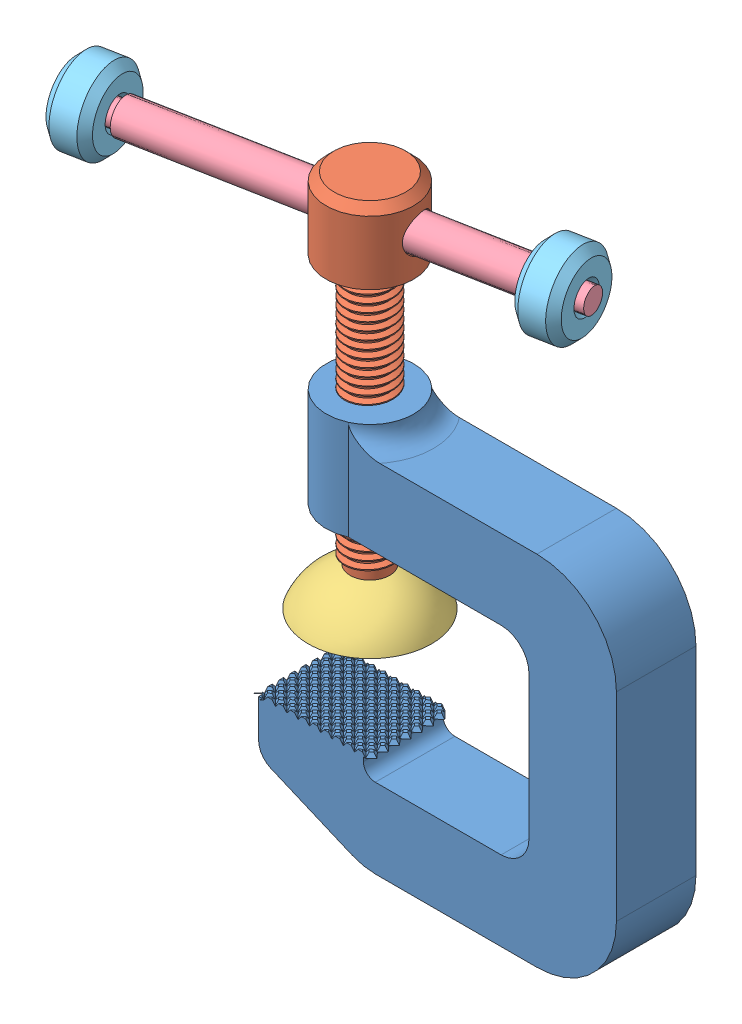
SolidWorks assembly Assem1, configuration Default. Lengths in mm.
Overall size (136.97 144.02 43.23).
6 component instances, 5 part files, 12 mates.
Components (placement in the parent):
- Part5-1: Part5 [Default] at (-108.175 29.7032 123.26) size (91.42 95.6 22.42)
- Part4-1: Part4 [Default] at (-90.175 55.0407 123.26) x (-0.186606 0 -0.982435) z (0.982435 0 -0.186606) size (22 93 22)
- Part3-1: Part3 [Default] at (-90.175 46.5848 123.26) x (0.840869 0 -0.541239) z (0.541239 0 0.840869) size (31 10.16 31)
- Part2-1: Part2 [Default] at (-43.0031 139.0407 114.3) x (-0.186606 0 -0.982435) z (0.982435 0 -0.186606) size (8.5 8.5 113)
- Part1-1: Part1 [Default] at (-153.275 139.0407 135.2454) x (0.982435 0 -0.186606) z (0.186606 0 0.982435) size (10 20 20)
- Part1-2: Part1 [Default] at (-54.1993 139.0407 116.4266) x (0.982435 0 -0.186606) z (0.186136 0.070968 0.979958) size (10 20 20)
Mates (geometry in assembly coordinates):
- Concentric1: concentric: cylinder of Part5-1 through (-90.175 100.7032 123.26) axis (0 -1 0) radius 11; cylinder of Part4-1 through (-90.175 55.0407 123.26) axis (0 -1 0) radius 11
- Coincident1: coincident: circle of Part5-1; cylinder of Part5-1 through (-90.175 100.7032 123.26) axis (0 -1 0) radius 11
- Coincident2: coincident: cylinder of Part4-1 through (-90.175 55.0407 123.26) axis (0 -1 0) radius 3; circle of Part3-1
- Concentric3: concentric: cylinder of Part4-1 through (-90.175 55.0407 123.26) axis (0 -1 0) radius 11; sphere of Part3-1
- Tangent5: tangent: circle of Part4-1; sphere of Part3-1
- Concentric4: concentric: cylinder of Part4-1 through (-100.9818 139.0407 125.3126) axis (0.982435 0 -0.186606) radius 4.5; cylinder of Part2-1 through (-43.0031 139.0407 114.3) axis (0.982435 0 -0.186606) radius 4.25
- Concentric5: concentric: cylinder of Part1-1 through (-153.275 139.0407 135.2454) axis (-0.982435 0 0.186606) radius 10; cylinder of Part1-2 through (-54.1993 139.0407 116.4266) axis (-0.982435 0 0.186606) radius 3
- Concentric6: concentric: cylinder of Part2-1 through (-43.0031 139.0407 114.3) axis (0.982435 0 -0.186606) radius 3; circle of Part1-2
- Concentric7: concentric: cylinder of Part2-1 through (-43.0031 139.0407 114.3) axis (0.982435 0 -0.186606) radius 3; cone of Part1-1 through (-143.4507 139.0407 133.3793) axis (-0.982435 0 0.186606)
- Concentric8: concentric: cylinder of Part2-1 through (-43.0031 139.0407 114.3) axis (0.982435 0 -0.186606) radius 3; cone of Part1-2 through (-44.3749 139.0407 114.5606) axis (-0.982435 0 0.186606)
- Concentric9: concentric: cylinder of Part2-1 through (-43.0031 139.0407 114.3) axis (0.982435 0 -0.186606) radius 3; cone of Part1-2 through (-44.3749 139.0407 114.5606) axis (-0.982435 0 0.186606)
- Concentric10: concentric: cylinder of Part2-1 through (-43.0031 139.0407 114.3) axis (0.982435 0 -0.186606) radius 3; cylinder of Part1-1 through (-153.275 139.0407 135.2454) axis (-0.982435 0 0.186606) radius 10
